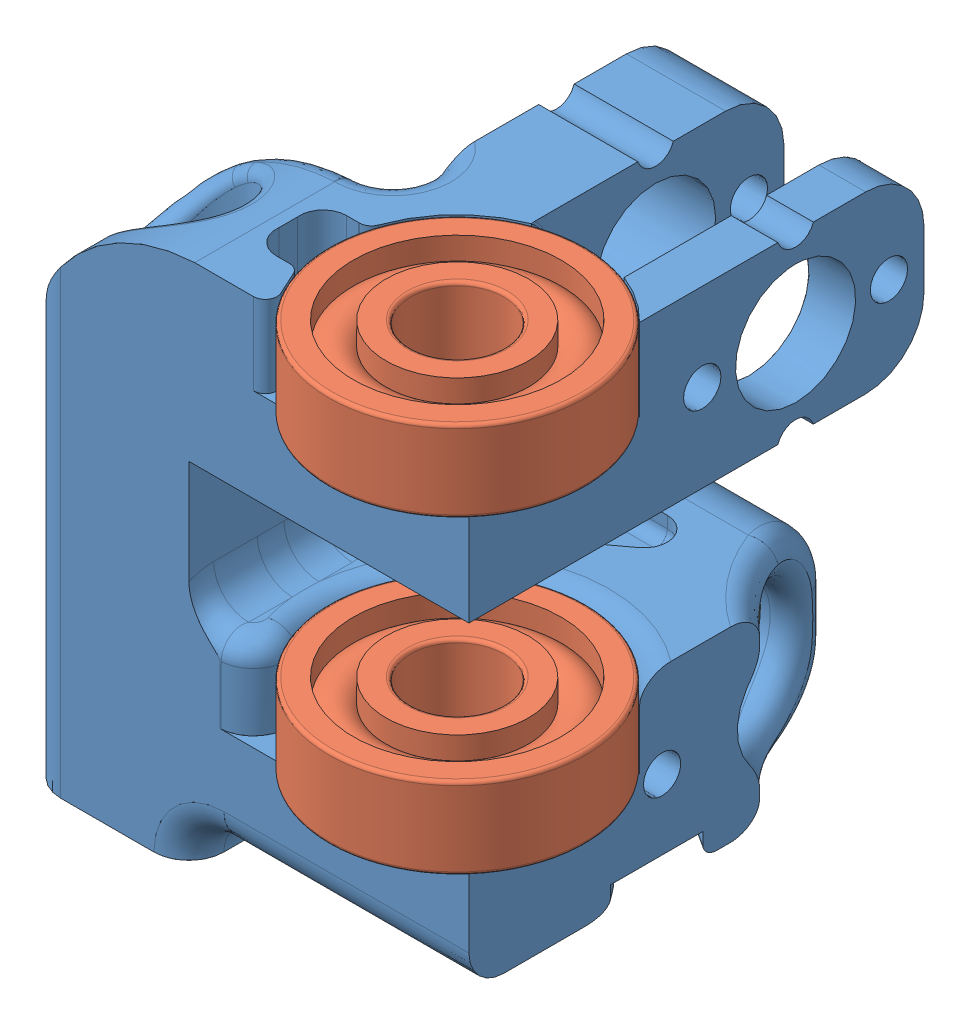
SolidWorks assembly x lead idler block, configuration Default. Lengths in mm.
Overall size (41 45.79 43).
4 component instances, 3 part files, 6 mates.
Components (placement in the parent):
- x idler lead mirror-1: x idler lead mirror [Default] at (2.4627 -2.0246 79.4222) size (39.6 45.79 39.15)
- instrument ball bearing_68_iso-1: instrument ball bearing_68_iso [ISO 1224 - 100822 - R,8,SI,NC,8_68] at (2.4627 -4.5246 72.4222) x (0 -1 0) z (0 0 1) size (7 22 22)
- instrument ball bearing_68_iso-2: instrument ball bearing_68_iso [ISO 1224 - 100822 - R,8,SI,NC,8_68] at (2.4627 21.9754 72.4222) x (0 1 0) z (0 0 1) size (7 22 22)
- brass sleeve 30mm-1: brass sleeve 30mm [Default] at (2.4627 -9.0246 51.4222) x (0 0 1) z (-1 0 0) size (11 11 30)
Mates (geometry in assembly coordinates):
- Concentrico2: concentric aligned: cylinder of x idler lead mirror-1 through (2.4627 -8.0246 72.4222) axis (0 1 0) radius 11.05; cylinder of instrument ball bearing_68_iso-2 through (2.4627 1.3379 72.4222) axis (0 1 0) radius 4
- Concentrico3: concentric anti-aligned: cylinder of x idler lead mirror-1 through (2.4627 18.4754 72.4222) axis (0 1 0) radius 11.05; cylinder of instrument ball bearing_68_iso-1 through (2.4627 16.1129 72.4222) axis (0 -1 0) radius 11
- Coincidente2: coincident aligned: plane of x idler lead mirror-1 through (-13.5373 25.4754 114.7634) normal (0 1 0); plane of instrument ball bearing_68_iso-2 through (-8.2373 25.4754 72.4222) normal (0 1 0)
- Coincidente3: coincident anti-aligned: plane of x idler lead mirror-1 through (2.4627 -8.0246 72.4222) normal (0 1 0); plane of instrument ball bearing_68_iso-1 through (13.1627 -8.0246 72.4222) normal (0 -1 0)
- Concentrico4: concentric anti-aligned: cylinder of x idler lead mirror-1 through (2.4627 -9.0246 51.4222) axis (-1 0 0) radius 5.6; cylinder of brass sleeve 30mm-1 through (-27.5373 -9.0246 51.4222) axis (1 0 0) radius 5.5
- Coincidente4: coincident aligned: plane of x idler lead mirror-1 through (-27.5373 47.9754 65.4222) normal (-1 0 0); plane of brass sleeve 30mm-1 through (-27.5373 -9.0246 51.4222) normal (-1 0 0)
